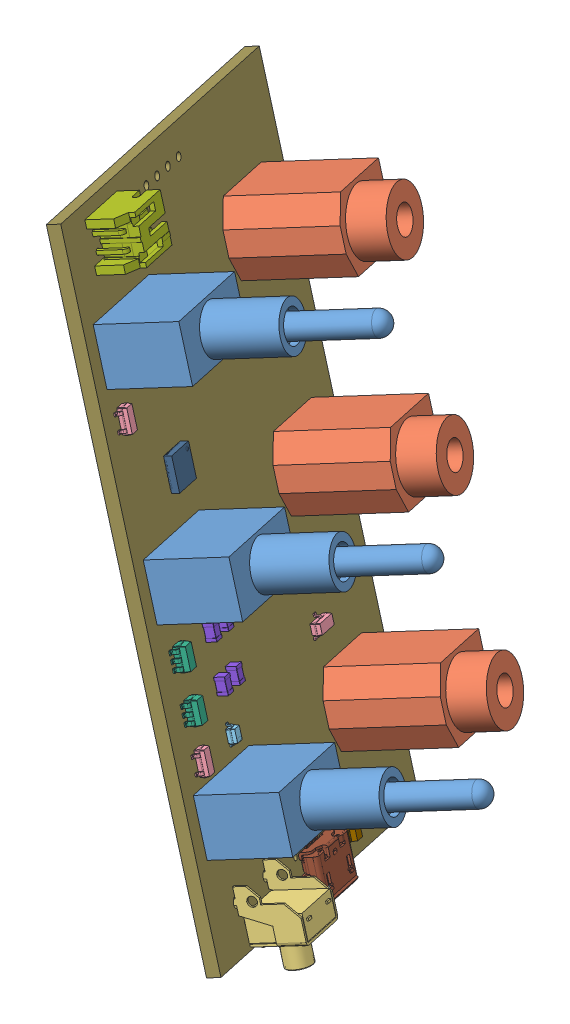
SolidWorks assembly PCB-assembly_v1.1, configuration Default. Lengths in mm.
Overall size (66.23 89.2 52.19).
102 component instances, 16 part files, 54 mates.
Components (placement in the parent):
- toggle-switch-4: toggle-switch [Default] at (-67.9927 86.0354 100.4663) x (0.334215 -0.940873 0.055309) z (0.337053 0.174117 0.925245) size (6.9 31.5 13.2)
- 3,5mmjack_MultiComp-1: 3,5mmjack_MultiComp [Default] at (-77.3391 81.8383 75.298) x (-0.334215 0.940873 -0.055309) z (0.880168 0.290588 -0.375317) size (9 10.5 21.9)
- ledTruckv1.1_new.step-1: ledTruckv1.1_new.step [Default] at (-61.225 73.4972 110.8928) x (-0.334215 0.940873 -0.055309) z (0.880168 0.290588 -0.375317) size (82.71 47 12.53)
  - PinHeader_1x04_P2.54mm_Vertical.step-1: PinHeader_1x04_P2.54mm_Vertical.step [Default] at (76.5862 -26.2915 1.65) x (-1 0 0) z (0 0 1) size (2.54 10.16 11.54) (hidden)
    - SOLID.step-1: SOLID.step [Default] at origin size (2.54 10.16 11.54)
  - R_0603_1608Metric.step-1: R_0603_1608Metric.step [Default] at (8.89 -22.225 1.65) x (-1 0 0) z (0 0 1) size (1.6 0.8 0.45)
    - SOLID-0.step-1: SOLID-0.step [Default] at origin size (1.6 0.8 0.45) (hidden)
  - R_0603_1608Metric.step-2: R_0603_1608Metric.step [Default] at (8.89 -24.003 1.65) size (1.6 0.8 0.45)
    - SOLID-0.step-1: SOLID-0.step [Default] at origin size (1.6 0.8 0.45) (hidden)
  - SW_Tactile_SPST_Angled_PTS645Vx58-2LFS.step-1: SW_Tactile_SPST_Angled_PTS645Vx58-2LFS.step [Default] at (3 -12 1.65) x (0 1 0) z (0 0 1) size (7.4 9.9 11)
    - SOLID-1.step-1: SOLID-1.step [Default] at origin size (7.4 9.9 11)
  - R_0603_1608Metric.step-3: R_0603_1608Metric.step [Default] at (26.416 -8.636 1.65) x (-1 0 0) z (0 0 1) size (1.6 0.8 0.45)
    - SOLID-0.step-1: SOLID-0.step [Default] at origin size (1.6 0.8 0.45) (hidden)
  - R_0603_1608Metric.step-4: R_0603_1608Metric.step [Default] at (21.082 -14.478 1.65) size (1.6 0.8 0.45)
    - SOLID-0.step-1: SOLID-0.step [Default] at origin size (1.6 0.8 0.45) (hidden)
  - R_0603_1608Metric.step-5: R_0603_1608Metric.step [Default] at (21.082 -8.636 1.65) x (-1 0 0) z (0 0 1) size (1.6 0.8 0.45)
    - SOLID-0.step-1: SOLID-0.step [Default] at origin size (1.6 0.8 0.45) (hidden)
  - R_0603_1608Metric.step-6: R_0603_1608Metric.step [Default] at (27.686 -35.052 1.65) x (-1 0 0) z (0 0 1) size (1.6 0.8 0.45)
    - SOLID-0.step-1: SOLID-0.step [Default] at origin size (1.6 0.8 0.45) (hidden)
  - SOT-23.step-1: SOT-23.step [Default] at (21.082 -4.572 1.65) x (0 -1 0) z (0 0 1) size (2.5 3 1.2)
    - SOLID-2.step-1: SOLID-2.step [Default] at origin size (2.5 3 1.2)
  - SOT-23.step-2: SOT-23.step [Default] at (31.496 -33.782 1.65) x (-1 0 0) z (0 0 1) size (2.5 3 1.2)
    - SOLID-2.step-1: SOLID-2.step [Default] at origin size (2.5 3 1.2)
  - SOT-23.step-3: SOT-23.step [Default] at (23.876 -33.782 1.65) size (2.5 3 1.2)
    - SOLID-2.step-1: SOLID-2.step [Default] at origin size (2.5 3 1.2)
  - D_SOD-323.step-1: D_SOD-323.step [Default] at (21.082 -11.684 1.65) size (2.5 1.25 1.1)
    - SOLID-3.step-1: SOLID-3.step [Default] at origin size (2.5 1.25 1.1)
  - C_0603_1608Metric.step-1: C_0603_1608Metric.step [Default] at (3.81 -3.556 1.65) size (1.6 0.8 0.8)
    - SOLID-4.step-1: SOLID-4.step [Default] at origin size (1.6 0.8 0.8) (hidden)
  - R_0603_1608Metric.step-7: R_0603_1608Metric.step [Default] at (51.938 -2.799 1.65) size (1.6 0.8 0.45)
    - SOLID-0.step-1: SOLID-0.step [Default] at origin size (1.6 0.8 0.45) (hidden)
  - SOT-23.step-4: SOT-23.step [Default] at (57.78 -3.688 1.65) x (0 -1 0) z (0 0 1) size (2.5 3 1.2)
    - SOLID-2.step-1: SOLID-2.step [Default] at origin size (2.5 3 1.2)
  - C_0603_1608Metric.step-2: C_0603_1608Metric.step [Default] at (51.938 -4.45 1.65) x (-1 0 0) z (0 0 1) size (1.6 0.8 0.8)
    - SOLID-4.step-1: SOLID-4.step [Default] at origin size (1.6 0.8 0.8) (hidden)
  - SOT-23-5.step-1: SOT-23-5.step [Default] at (32.126 -4.704 1.65) x (0 -1 0) z (0 0 1) size (2.8 2.9 1.55)
    - SOLID-5.step-1: SOLID-5.step [Default] at origin size (2.8 2.9 1.55)
  - SOT-23-5.step-2: SOT-23-5.step [Default] at (26.416 -4.699 1.65) x (0 -1 0) z (0 0 1) size (2.8 2.9 1.55)
    - SOLID-5.step-1: SOLID-5.step [Default] at origin size (2.8 2.9 1.55)
  - JST_PH_S2B-PH-K_1x02_P2.00mm_Horizontal.step-1: JST_PH_S2B-PH-K_1x02_P2.00mm_Horizontal.step [Default] at (74.544 -6.228 1.65) size (5.9 7.6 8.25)
    - SOLID-6.step-1: SOLID-6.step [Default] at origin size (5.9 7.6 8.25)
  - R_0603_1608Metric.step-8: R_0603_1608Metric.step [Default] at (57.1958 -32.8676 1.65) x (-1 0 0) z (0 0 1) size (1.6 0.8 0.45)
    - SOLID-0.step-1: SOLID-0.step [Default] at origin size (1.6 0.8 0.45) (hidden)
  - R_0603_1608Metric.step-9: R_0603_1608Metric.step [Default] at (57.526 -8.006 1.65) size (1.6 0.8 0.45)
    - SOLID-0.step-1: SOLID-0.step [Default] at origin size (1.6 0.8 0.45) (hidden)
  - R_0603_1608Metric.step-10: R_0603_1608Metric.step [Default] at (57.526 -6.355 1.65) x (-1 0 0) z (0 0 1) size (1.6 0.8 0.45)
    - SOLID-0.step-1: SOLID-0.step [Default] at origin size (1.6 0.8 0.45) (hidden)
  - R_0603_1608Metric.step-11: R_0603_1608Metric.step [Default] at (5.969 -36.068 1.65) x (0 -1 0) z (0 0 1) size (1.6 0.8 0.45)
    - SOLID-0.step-1: SOLID-0.step [Default] at origin size (1.6 0.8 0.45) (hidden)
  - R_0603_1608Metric.step-12: R_0603_1608Metric.step [Default] at (5.9944 -31.4706 1.65) x (0 1 0) z (0 0 1) size (1.6 0.8 0.45)
    - SOLID-0.step-1: SOLID-0.step [Default] at origin size (1.6 0.8 0.45) (hidden)
  - R_0603_1608Metric.step-13: R_0603_1608Metric.step [Default] at (46.604 -7.752 1.65) size (1.6 0.8 0.45)
    - SOLID-0.step-1: SOLID-0.step [Default] at origin size (1.6 0.8 0.45) (hidden)
  - R_0603_1608Metric.step-14: R_0603_1608Metric.step [Default] at (59.812 -12.705 1.65) x (0 1 0) z (0 0 1) size (1.6 0.8 0.45)
    - SOLID-0.step-1: SOLID-0.step [Default] at origin size (1.6 0.8 0.45) (hidden)
  - R_0603_1608Metric.step-15: R_0603_1608Metric.step [Default] at (32.1514 -8.636 1.65) x (-1 0 0) z (0 0 1) size (1.6 0.8 0.45)
    - SOLID-0.step-1: SOLID-0.step [Default] at origin size (1.6 0.8 0.45) (hidden)
  - R_0603_1608Metric.step-16: R_0603_1608Metric.step [Default] at (51.938 -38.994 1.65) x (-1 0 0) z (0 0 1) size (1.6 0.8 0.45)
    - SOLID-0.step-1: SOLID-0.step [Default] at origin size (1.6 0.8 0.45) (hidden)
  - R_0603_1608Metric.step-17: R_0603_1608Metric.step [Default] at (51.938 -34.93 1.65) size (1.6 0.8 0.45)
    - SOLID-0.step-1: SOLID-0.step [Default] at origin size (1.6 0.8 0.45) (hidden)
  - R_0603_1608Metric.step-18: R_0603_1608Metric.step [Default] at (27.686 -36.957 1.65) size (1.6 0.8 0.45)
    - SOLID-0.step-1: SOLID-0.step [Default] at origin size (1.6 0.8 0.45) (hidden)
  - R_0603_1608Metric.step-19: R_0603_1608Metric.step [Default] at (51.938 -36.962 1.65) x (-1 0 0) z (0 0 1) size (1.6 0.8 0.45)
    - SOLID-0.step-1: SOLID-0.step [Default] at origin size (1.6 0.8 0.45) (hidden)
  - R_0603_1608Metric.step-20: R_0603_1608Metric.step [Default] at (51.9176 -32.9184 1.65) x (-1 0 0) z (0 0 1) size (1.6 0.8 0.45)
    - SOLID-0.step-1: SOLID-0.step [Default] at origin size (1.6 0.8 0.45) (hidden)
  - R_0603_1608Metric.step-21: R_0603_1608Metric.step [Default] at (27.686 -38.862 1.65) size (1.6 0.8 0.45)
    - SOLID-0.step-1: SOLID-0.step [Default] at origin size (1.6 0.8 0.45) (hidden)
  - C_0805_2012Metric.step-1: C_0805_2012Metric.step [Default] at (26.416 -14.478 1.65) x (-1 0 0) z (0 0 1) size (2 1.25 1.25)
    - SOLID-7.step-1: SOLID-7.step [Default] at origin size (2 1.25 1.25)
  - C_0603_1608Metric.step-3: C_0603_1608Metric.step [Default] at (46.604 -6.101 1.65) x (-1 0 0) z (0 0 1) size (1.6 0.8 0.8)
    - SOLID-4.step-1: SOLID-4.step [Default] at origin size (1.6 0.8 0.8) (hidden)
  - C_0805_2012Metric.step-2: C_0805_2012Metric.step [Default] at (32.126 -11.689 1.65) size (2 1.25 1.25)
    - SOLID-7.step-1: SOLID-7.step [Default] at origin size (2 1.25 1.25)
  - C_0603_1608Metric.step-4: C_0603_1608Metric.step [Default] at (46.604 -4.45 1.65) size (1.6 0.8 0.8)
    - SOLID-4.step-1: SOLID-4.step [Default] at origin size (1.6 0.8 0.8) (hidden)
  - C_0603_1608Metric.step-5: C_0603_1608Metric.step [Default] at (46.604 -2.799 1.65) size (1.6 0.8 0.8)
    - SOLID-4.step-1: SOLID-4.step [Default] at origin size (1.6 0.8 0.8) (hidden)
  - C_0805_2012Metric.step-3: C_0805_2012Metric.step [Default] at (26.416 -11.684 1.65) x (-1 0 0) z (0 0 1) size (2 1.25 1.25)
    - SOLID-7.step-1: SOLID-7.step [Default] at origin size (2 1.25 1.25)
  - C_0603_1608Metric.step-6: C_0603_1608Metric.step [Default] at (57.526 -9.657 1.65) size (1.6 0.8 0.8)
    - SOLID-4.step-1: SOLID-4.step [Default] at origin size (1.6 0.8 0.8) (hidden)
  - C_0603_1608Metric.step-7: C_0603_1608Metric.step [Default] at (57.526 -15.626 1.65) size (1.6 0.8 0.8)
    - SOLID-4.step-1: SOLID-4.step [Default] at origin size (1.6 0.8 0.8) (hidden)
  - C_0805_2012Metric.step-4: C_0805_2012Metric.step [Default] at (32.126 -14.478 1.65) size (2 1.25 1.25)
    - SOLID-7.step-1: SOLID-7.step [Default] at origin size (2 1.25 1.25)
  - LED_0805_2012Metric.step-1: LED_0805_2012Metric.step [Default] at (2.6589 -36 1.65) x (0 -1 0) z (0 0 1) size (2 1.25 1.1)
    - SOLID-8.step-1: SOLID-8.step [Default] at origin size (2 1.25 1.1)
  - LED_0805_2012Metric.step-2: LED_0805_2012Metric.step [Default] at (2.6589 -31.45 1.65) x (0 -1 0) z (0 0 1) size (2 1.25 1.1)
    - SOLID-8.step-1: SOLID-8.step [Default] at origin size (2 1.25 1.1)
  - QFN-32-1EP_4x4mm_P0.4mm_EP2.65x2.65mm.step-1: QFN-32-1EP_4x4mm_P0.4mm_EP2.65x2.65mm.step [Default] at (49.136 -12.5 1.65) x (-1 0 0) z (0 0 1) size (4 4 0.92)
    - SOLID-9.step-1: SOLID-9.step [Default] at origin size (4 4 0.92)
  - USB_Micro-B_Molex_47346-0001.step-1: USB_Micro-B_Molex_47346-0001.step [Default] at (3.3873 -23.4924 1.65) x (0 -1 0) z (0 0 1) size (7.98 5.42 2.94)
    - SOLID-10.step-1: SOLID-10.step [Default] at origin size (7.98 5.42 2.94)
  - Crystal_SMD_0603-4Pin_6.0x3.5mm.step-1: Crystal_SMD_0603-4Pin_6.0x3.5mm.step [Default] at (57.526 -12.705 1.65) x (0 1 0) z (0 0 1) size (6 3.5 1.03)
    - SOLID-11.step-1: SOLID-11.step [Default] at origin size (6 3.5 1.03) (hidden)
  - COMPOUND.step-1: COMPOUND.step [Default] at origin size (80 47 1.6)
- toggle-switch-5: toggle-switch [Default] at (-76.348 109.5572 99.0835) x (0.334215 -0.940873 0.055309) z (0.337053 0.174117 0.925245) size (6.9 31.5 13.2)
- toggle-switch-6: toggle-switch [Default] at (-84.7034 133.079 97.7008) x (0.334215 -0.940873 0.055309) z (0.337053 0.174117 0.925245) size (6.9 31.5 13.2)
- 3,5mmjack_MultiComp-6: 3,5mmjack_MultiComp [Default] at (-85.6945 105.3601 73.9153) x (-0.334215 0.940873 -0.055309) z (0.880168 0.290588 -0.375317) size (9 10.5 21.9)
- 3,5mmjack_MultiComp-7: 3,5mmjack_MultiComp [Default] at (-94.0499 128.882 72.5326) x (-0.334215 0.940873 -0.055309) z (0.880168 0.290588 -0.375317) size (9 10.5 21.9)
Mates (geometry in assembly coordinates):
- Coincident1: coincident anti-aligned: plane of ledTruck_PCB.step-1/ledTruck.step-1/COMPOUND.step-1 through (-73.1659 -1.8596 36.9841) normal (0 0 1); plane of 3,5mmjack-1 through (-98.1659 -15.3596 36.9841) normal (0 0 -1)
- Coincident2: coincident anti-aligned: plane of ledTruck_PCB.step-1/ledTruck.step-1/COMPOUND.step-1 through (-100.2659 -16.2596 35.3841) normal (-1 0 0); plane of 3,5mmjack-1 through (-100.2659 -14.4596 34.9841) normal (1 0 0)
- Coincident3: coincident anti-aligned: plane of ledTruck_PCB.step-1/ledTruck.step-1/COMPOUND.step-1 through (-99.0659 -13.2596 35.3841) normal (0 1 0); plane of 3,5mmjack-1 through (-97.2659 -13.2596 34.9841) normal (0 -1 0)
- Coincident4: coincident anti-aligned: plane of ledTruck_PCB.step-1/ledTruck.step-1/COMPOUND.step-1 through (-73.1659 -1.8596 36.9841) normal (0 0 1); plane of 3,5mmjack-2 through (-73.1659 -15.3596 36.9841) normal (0 0 -1)
- Coincident5: coincident anti-aligned: plane of ledTruck_PCB.step-1/ledTruck.step-1/COMPOUND.step-1 through (-75.2659 -16.2596 35.3841) normal (-1 0 0); plane of 3,5mmjack-2 through (-75.2659 -14.4596 34.9841) normal (1 0 0)
- Coincident6: coincident anti-aligned: plane of ledTruck_PCB.step-1/ledTruck.step-1/COMPOUND.step-1 through (-73.1659 -1.8596 36.9841) normal (0 0 1); plane of 3,5mmjack-3 through (-48.1659 -15.3596 36.9841) normal (0 0 -1)
- Coincident7: coincident anti-aligned: plane of ledTruck_PCB.step-1/ledTruck.step-1/COMPOUND.step-1 through (-50.2659 -16.2596 35.3841) normal (-1 0 0); plane of 3,5mmjack-3 through (-50.2659 -14.4596 34.9841) normal (1 0 0)
- Coincident8: coincident anti-aligned: plane of ledTruck_PCB.step-1/ledTruck.step-1/COMPOUND.step-1 through (-49.0659 -13.2596 35.3841) normal (0 1 0); plane of 3,5mmjack-3 through (-47.2659 -13.2596 34.9841) normal (0 -1 0)
- Coincident12: coincident anti-aligned: plane of ledTruck_PCB.step-1/ledTruck.step-1/COMPOUND.step-1 through (-74.0659 -13.2596 35.3841) normal (0 1 0); plane of 3,5mmjack-2 through (-72.2659 -13.2596 34.9841) normal (0 -1 0)
- Coincident13: coincident anti-aligned: plane of ledTruck_PCB.step-1/ledTruck.step-1/COMPOUND.step-1 through (-73.1659 -1.8596 36.9841) normal (0 0 1); plane of toggle-switch-2 through (-18.9819 47.5049 38.7522) normal (0 0 -1)
- Coincident14: coincident anti-aligned: plane of ledTruck_PCB.step-1/ledTruck.step-1/COMPOUND.step-1 through (-47.5659 8.7904 35.3841) normal (0 -1 0); plane of toggle-switch-2 through (-19.9466 42.3912 36.5522) normal (0 1 0)
- Concentric5: concentric anti-aligned: cylinder of ledTruck_PCB.step-1/ledTruck.step-1/COMPOUND.step-1 through (-47.5659 8.1404 35.3841) axis (0 0 -1) radius 0.65; cylinder of toggle-switch-2 through (-18.7466 41.7412 36.5522) axis (0 0 1) radius 0.65
- Coincident17: coincident anti-aligned: plane of ledTruck_PCB.step-1/ledTruck.step-1/COMPOUND.step-1 through (-73.1659 -1.8596 36.9841) normal (0 0 1); plane of toggle-switch-3 through (-48.8864 61.1587 42.7227) normal (0 0 -1)
- Coincident18: coincident anti-aligned: plane of ledTruck_PCB.step-1/ledTruck.step-1/COMPOUND.step-1 through (-72.5659 8.7904 35.3841) normal (0 -1 0); plane of toggle-switch-3 through (-49.851 56.045 40.5227) normal (0 1 0)
- Concentric6: concentric anti-aligned: cylinder of ledTruck_PCB.step-1/ledTruck.step-1/COMPOUND.step-1 through (-72.5659 8.1404 35.3841) axis (0 0 -1) radius 0.65; cylinder of toggle-switch-3 through (-48.651 55.395 40.5227) axis (0 0 1) radius 0.65
- Coincident19: coincident anti-aligned: plane of ledTruck_PCB.step-1/ledTruck.step-1/COMPOUND.step-1 through (-73.1659 -1.8596 36.9841) normal (0 0 1); plane of toggle-switch-4 through (-67.9927 86.0354 100.4663) normal (-0.880168 -0.290588 0.375317)
- Coincident20: coincident anti-aligned: plane of ledTruck_PCB.step-1/ledTruck.step-1/COMPOUND.step-1 through (-97.5659 8.7904 35.3841) normal (0 -1 0); plane of toggle-switch-4 through (-68.5279 87.194 105.97) normal (-0.337053 -0.174117 -0.925245)
- Concentric7: concentric anti-aligned: cylinder of ledTruck_PCB.step-1/ledTruck.step-1/COMPOUND.step-1 through (-97.5659 8.1404 35.3841) axis (0 0 -1) radius 0.65; cylinder of toggle-switch-4 through (-67.9077 86.1782 106.6378) axis (0.880168 0.290588 -0.375317) radius 0.65
- Coincident22: coincident anti-aligned: plane of ledTruck_PCB.step-1/ledTruck.step-1/COMPOUND.step-1 through (-73.1659 -1.8596 36.9841) normal (0 0 1); plane of slideswitch-1 through (-109.6165 12.0841 36.9841) normal (0 0 -1)
- Concentric8: concentric aligned: cylinder of ledTruck_PCB.step-1/ledTruck.step-1/COMPOUND.step-1 through (-108.7259 14.6404 34.5841) axis (0 0 1) radius 0.5; cylinder of slideswitch-1 through (-108.7259 14.6404 34.7841) axis (0 0 1) radius 0.4
- Concentric9: concentric aligned: cylinder of ledTruck_PCB.step-1/ledTruck.step-1/COMPOUND.step-1 through (-108.7259 11.6404 34.5841) axis (0 0 1) radius 0.5; cylinder of slideswitch-1 through (-108.7259 11.6404 34.7841) axis (0 0 1) radius 0.4
- Coincident25: coincident anti-aligned: plane of ledTruck_PCB.step-1/ledTruck.step-1/COMPOUND.step-1 through (-73.1659 -1.8596 36.9841) normal (0 0 1); plane of 3,5mmjack_MultiComp-4 through (0.0015 35.2805 33.8495) normal (0 0 -1)
- Distance6: distance = 40 mm: cylinder of 3,5mmjack_MultiComp-4 through (-0.2008 35.1935 36.8495) axis (0 0 1) radius 1.75; plane of ledTruck_PCB.step-1/ledTruck.step-1/COMPOUND.step-1 through (-113.1659 -25.3596 35.3841) normal (-1 0 0)
- Distance7: distance = 10 mm: cylinder of 3,5mmjack_MultiComp-4 through (-0.2008 35.1935 36.8495) axis (0 0 1) radius 1.75; plane of ledTruck_PCB.step-1/ledTruck.step-1/COMPOUND.step-1 through (-33.1659 -25.3596 35.3841) normal (0 -1 0)
- Parallel2: parallel aligned: plane of ledTruck_PCB.step-1/ledTruck.step-1/COMPOUND.step-1 through (-33.1659 -25.3596 35.3841) normal (0 -1 0); plane of 3,5mmjack_MultiComp-4 through (-4.7008 29.6935 46.8495) normal (0 -1 0)
- Coincident26: coincident anti-aligned: plane of ledTruck_PCB.step-1/ledTruck.step-1/COMPOUND.step-1 through (-73.1659 -1.8596 36.9841) normal (0 0 1); plane of 3,5mmjack_MultiComp-5 through (-47.9637 -15.2725 36.9841) normal (0 0 -1)
- Distance8: distance = 65 mm: cylinder of 3,5mmjack_MultiComp-5 through (-48.1659 -15.3596 39.9841) axis (0 0 1) radius 1.75; plane of ledTruck_PCB.step-1/ledTruck.step-1/COMPOUND.step-1 through (-113.1659 -25.3596 35.3841) normal (-1 0 0)
- Distance9: distance = 10 mm: cylinder of 3,5mmjack_MultiComp-5 through (-48.1659 -15.3596 39.9841) axis (0 0 1) radius 1.75; plane of ledTruck_PCB.step-1/ledTruck.step-1/COMPOUND.step-1 through (-33.1659 -25.3596 35.3841) normal (0 -1 0)
- Parallel3: parallel aligned: plane of ledTruck_PCB.step-1/ledTruck.step-1/COMPOUND.step-1 through (-33.1659 -25.3596 35.3841) normal (0 -1 0); plane of 3,5mmjack_MultiComp-5 through (-52.6659 -20.8596 49.9841) normal (0 -1 0)
- Coincident27: coincident anti-aligned: plane of ledTruck_PCB.step-1/ledTruck.step-1/COMPOUND.step-1 through (-73.1659 -1.8596 36.9841) normal (0 0 1); plane of 3,5mmjack_MultiComp-6 through (-85.6945 105.3601 73.9153) normal (-0.880168 -0.290588 0.375317)
- Distance10: distance = 65 mm: cylinder of 3,5mmjack_MultiComp-6 through (-83.0158 106.0265 72.72) axis (0.880168 0.290588 -0.375317) radius 1.75; plane of ledTruck_PCB.step-1/ledTruck.step-1/COMPOUND.step-1 through (-113.1659 -25.3596 35.3841) normal (-1 0 0)
- Distance11: distance = 10 mm: cylinder of 3,5mmjack_MultiComp-6 through (-83.0158 106.0265 72.72) axis (0.880168 0.290588 -0.375317) radius 1.75; plane of ledTruck_PCB.step-1/ledTruck.step-1/COMPOUND.step-1 through (-33.1659 -25.3596 35.3841) normal (0 -1 0)
- Parallel4: parallel aligned: plane of ledTruck_PCB.step-1/ledTruck.step-1/COMPOUND.step-1 through (-33.1659 -25.3596 35.3841) normal (0 -1 0); plane of 3,5mmjack_MultiComp-6 through (-74.5639 103.7408 64.1268) normal (-0.337053 -0.174117 -0.925245)
- Coincident31: coincident anti-aligned: plane of toggle-switch-4 through (-67.9927 86.0354 100.4663) normal (-0.880168 -0.290588 0.375317); plane of ledTruckv1.1_new.step-1/COMPOUND.step-1 through (-81.106 107.5053 86.3367) normal (0.880168 0.290588 -0.375317)
- Coincident33: coincident anti-aligned: plane of 3,5mmjack_MultiComp-1 through (-77.3391 81.8383 75.298) normal (-0.880168 -0.290588 0.375317); plane of ledTruckv1.1_new.step-1/COMPOUND.step-1 through (-81.106 107.5053 86.3367) normal (0.880168 0.290588 -0.375317)
- Coincident37: coincident anti-aligned: plane of ledTruckv1.1_new.step-1/COMPOUND.step-1 through (-81.106 107.5053 86.3367) normal (0.880168 0.290588 -0.375317); plane of toggle-switch-5 through (-76.348 109.5572 99.0835) normal (-0.880168 -0.290588 0.375317)
- Coincident40: coincident anti-aligned: plane of ledTruckv1.1_new.step-1/COMPOUND.step-1 through (-81.106 107.5053 86.3367) normal (0.880168 0.290588 -0.375317); plane of toggle-switch-6 through (-84.7434 133.0583 97.5911) normal (-0.880168 -0.290588 0.375317)
- Coincident44: coincident anti-aligned: plane of ledTruckv1.1_new.step-1/COMPOUND.step-1 through (-81.106 107.5053 86.3367) normal (0.880168 0.290588 -0.375317); plane of 3,5mmjack_MultiComp-6 through (-85.6945 105.3601 73.9153) normal (-0.880168 -0.290588 0.375317)
- Coincident47: coincident anti-aligned: plane of ledTruckv1.1_new.step-1/COMPOUND.step-1 through (-81.106 107.5053 86.3367) normal (0.880168 0.290588 -0.375317); plane of 3,5mmjack_MultiComp-7 through (-94.0499 128.882 72.5326) normal (-0.880168 -0.290588 0.375317)
- Distance12: distance = 15 mm: cylinder of 3,5mmjack_MultiComp-1 through (-74.6604 82.5046 74.1027) axis (0.880168 0.290588 -0.375317) radius 1.75; line of ledTruckv1.1_new.step-1/COMPOUND.step-1 through (-75.6582 65.7786 66.8058) axis (0.337053 0.174117 0.925245)
- Distance13: distance = 37 mm: cylinder of 3,5mmjack_MultiComp-1 through (-74.6604 82.5046 74.1027) axis (0.880168 0.290588 -0.375317) radius 1.75; line of ledTruckv1.1_new.step-1/COMPOUND.step-1 through (-59.8167 73.9621 110.2923) axis (-0.334215 0.940873 -0.055309)
- Parallel8: parallel aligned: plane of 3,5mmjack_MultiComp-1 through (-66.2085 80.219 65.5096) normal (-0.337053 -0.174117 -0.925245); plane of ledTruckv1.1_new.step-1/COMPOUND.step-1 through (-103.8036 140.5835 62.9816) normal (-0.337053 -0.174117 -0.925245)
- Distance14: distance = 40 mm: cylinder of 3,5mmjack_MultiComp-6 through (-83.0158 106.0265 72.72) axis (0.880168 0.290588 -0.375317) radius 1.75; line of ledTruckv1.1_new.step-1/COMPOUND.step-1 through (-75.6582 65.7786 66.8058) axis (0.337053 0.174117 0.925245)
- Distance15: distance = 37 mm: cylinder of 3,5mmjack_MultiComp-6 through (-83.0158 106.0265 72.72) axis (0.880168 0.290588 -0.375317) radius 1.75; line of ledTruckv1.1_new.step-1/COMPOUND.step-1 through (-59.8167 73.9621 110.2923) axis (-0.334215 0.940873 -0.055309)
- Parallel11: parallel aligned: plane of ledTruckv1.1_new.step-1/COMPOUND.step-1 through (-103.8036 140.5835 62.9816) normal (-0.337053 -0.174117 -0.925245); plane of 3,5mmjack_MultiComp-6 through (-74.5639 103.7408 64.1268) normal (-0.337053 -0.174117 -0.925245)
- Distance16: distance = 65 mm: cylinder of 3,5mmjack_MultiComp-7 through (-91.3711 129.5483 71.3373) axis (0.880168 0.290588 -0.375317) radius 1.75; line of ledTruckv1.1_new.step-1/COMPOUND.step-1 through (-75.6582 65.7786 66.8058) axis (0.337053 0.174117 0.925245)
- Distance17: distance = 37 mm: cylinder of 3,5mmjack_MultiComp-7 through (-91.3711 129.5483 71.3373) axis (0.880168 0.290588 -0.375317) radius 1.75; line of ledTruckv1.1_new.step-1/COMPOUND.step-1 through (-59.8167 73.9621 110.2923) axis (-0.334215 0.940873 -0.055309)
- Parallel14: parallel aligned: plane of ledTruckv1.1_new.step-1/COMPOUND.step-1 through (-103.8036 140.5835 62.9816) normal (-0.337053 -0.174117 -0.925245); plane of 3,5mmjack_MultiComp-7 through (-82.9193 127.2626 62.7441) normal (-0.337053 -0.174117 -0.925245)
- Distance18: distance = 15 mm: cylinder of toggle-switch-4 through (-51.6889 91.8608 94.4523) axis (-0.880168 -0.290588 0.375317) radius 3; line of ledTruckv1.1_new.step-1/COMPOUND.step-1 through (-75.6582 65.7786 66.8058) axis (0.337053 0.174117 0.925245)
- Distance19: distance = 40 mm: cylinder of toggle-switch-5 through (-60.0443 115.3826 93.0695) axis (-0.880168 -0.290588 0.375317) radius 3; line of ledTruckv1.1_new.step-1/COMPOUND.step-1 through (-75.6582 65.7786 66.8058) axis (0.337053 0.174117 0.925245)
- Distance20: distance = 65 mm: cylinder of toggle-switch-6 through (-68.3996 138.9044 91.6868) axis (-0.880168 -0.290588 0.375317) radius 3; line of ledTruckv1.1_new.step-1/COMPOUND.step-1 through (-75.6582 65.7786 66.8058) axis (0.337053 0.174117 0.925245)
- Distance21: distance = 8.8 mm: cylinder of toggle-switch-4 through (-51.6889 91.8608 94.4523) axis (-0.880168 -0.290588 0.375317) radius 3; line of ledTruckv1.1_new.step-1/COMPOUND.step-1 through (-59.8167 73.9621 110.2923) axis (-0.334215 0.940873 -0.055309)
- Distance22: distance = 8.8 mm: cylinder of toggle-switch-5 through (-60.0443 115.3826 93.0695) axis (-0.880168 -0.290588 0.375317) radius 3; line of ledTruckv1.1_new.step-1/COMPOUND.step-1 through (-59.8167 73.9621 110.2923) axis (-0.334215 0.940873 -0.055309)
- Distance23: distance = 8.8 mm: cylinder of toggle-switch-6 through (-68.3996 138.9044 91.6868) axis (-0.880168 -0.290588 0.375317) radius 3; line of ledTruckv1.1_new.step-1/COMPOUND.step-1 through (-59.8167 73.9621 110.2923) axis (-0.334215 0.940873 -0.055309)
